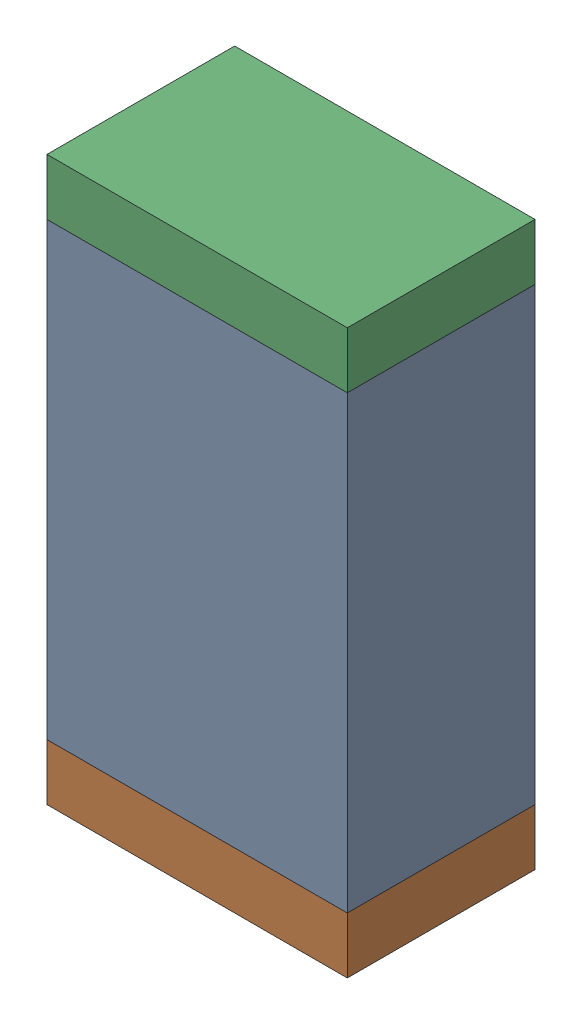
SolidWorks assembly C82, configuration Default. Lengths in mm.
Overall size (0.8 1.5 0.5).
6 component instances, 2 part files, 0 mates.
Components (placement in the parent):
- 810156976-1: 810156976 [Default] at (108.15 62.1 0) size (0.8 1.2 0.5)
  - Extruded_6-1: Extruded_6 [Default] at origin size (0.8 1.2 0.5)
- 810156592-1: 810156592 [Default] at (108.15 61.425 0) size (0.8 0.15 0.5)
  - Extruded_7-1: Extruded_7 [Default] at origin size (0.8 0.15 0.5)
- 810156592-2: 810156592 [Default] at (108.15 62.775 0) size (0.8 0.15 0.5)
  - Extruded_7-1: Extruded_7 [Default] at origin size (0.8 0.15 0.5)
